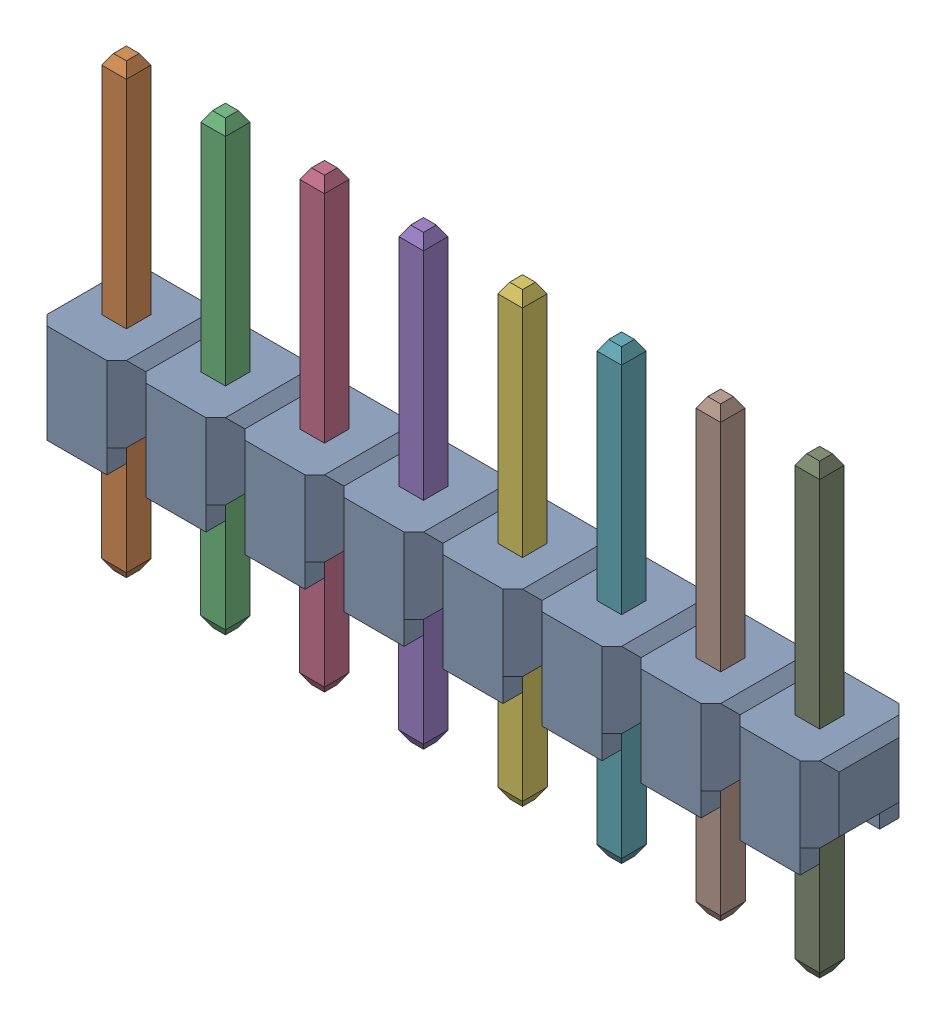
SolidWorks assembly M20-977_ASM, configuration Default. Lengths in mm.
Overall size (20.32 11.48 2.54).
9 component instances, 2 part files, 0 mates.
Components (placement in the parent):
- M20-977-MOULD_2-1: M20-977-MOULD_2 [Default] at origin size (20.32 2.54 2.54)
- M20-977-PIN.7-1: M20-977-PIN.7 [Default] at (2.54 -5.68 0) x (1 0 0) z (0 0 -1) size (0.64 11.48 0.64)
- M20-977-PIN.7-2: M20-977-PIN.7 [Default] at (5.08 -5.68 0) x (1 0 0) z (0 0 -1) size (0.64 11.48 0.64)
- M20-977-PIN.7-3: M20-977-PIN.7 [Default] at (7.62 -5.68 0) x (1 0 0) z (0 0 -1) size (0.64 11.48 0.64)
- M20-977-PIN.7-4: M20-977-PIN.7 [Default] at (10.16 -5.68 0) x (1 0 0) z (0 0 -1) size (0.64 11.48 0.64)
- M20-977-PIN.7-5: M20-977-PIN.7 [Default] at (12.7 -5.68 0) x (1 0 0) z (0 0 -1) size (0.64 11.48 0.64)
- M20-977-PIN.7-6: M20-977-PIN.7 [Default] at (15.24 -5.68 0) x (1 0 0) z (0 0 -1) size (0.64 11.48 0.64)
- M20-977-PIN.7-7: M20-977-PIN.7 [Default] at (17.78 -5.68 0) x (1 0 0) z (0 0 -1) size (0.64 11.48 0.64)
- M20-977-PIN.7-8: M20-977-PIN.7 [Default] at (20.32 -5.68 0) x (1 0 0) z (0 0 -1) size (0.64 11.48 0.64)
